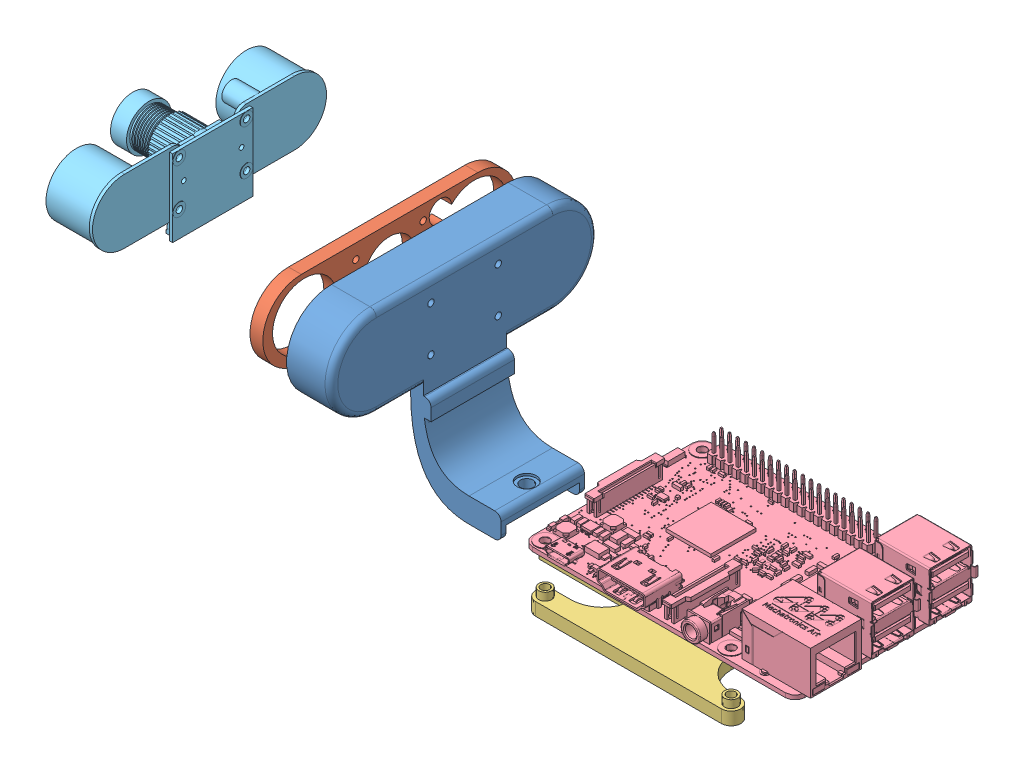
SolidWorks assembly Assem1, configuration Default. Lengths in mm.
Overall size (236.84 58 83.09).
5 component instances, 5 part files, 11 mates.
Components (placement in the parent):
- coverbase-1: coverbase [Default] at (37.3984 -15.5454 69.6534) x (0 0 1) z (-1 0 0) size (83.09 58 38.24)
- coverfront-1: coverfront [Default] at (13.9856 -17.5454 69.6493) x (0 0 1) z (-1 0 0) size (79.08 27.03 4)
- basecover-1: basecover [Default] at (103.6541 -46.1655 93.5452) size (76.61 6.4 55)
- Raspberry Pi 3-1: Raspberry Pi 3 [Default] at (131.8364 -28.3463 80.8971) x (1 0 0) z (0 1 0) size (89.64 57.31 18.59)
- Camera Module NVision Assem-1: Camera Module NVision Assem [Default] at (-21.6732 -17.5454 69.6534) x (0 0 1) z (-1 0 0) size (73 25 24.98)
Mates (geometry in assembly coordinates):
- Coincident1: coincident aligned: plane of coverbase-1 through (51.6361 -46.1655 65.4864) normal (0 -1 0); plane of basecover-1 through (103.6541 -46.1655 93.5452) normal (0 -1 0)
- Parallel1: parallel aligned: plane of coverbase-1 through (33.3984 -15.5454 65.4864) normal (0 0 -1); plane of basecover-1 through (103.6541 -42.1655 66.9864) normal (0 0 -1)
- Coincident4: coincident anti-aligned: plane of coverbase-1 through (52.6361 -46.1655 89.9864) normal (0 0 -1); plane of basecover-1 through (103.6541 -42.1655 89.9864) normal (0 0 1)
- Parallel2: parallel anti-aligned: plane of basecover-1 through (103.6541 -42.1655 93.5452) normal (0 1 0); plane of Raspberry Pi 3-1 through (168.3186 -28.6763 50.4864) normal (0 -1 0)
- Parallel3: parallel aligned: plane of coverbase-1 through (33.3984 -15.5454 65.4864) normal (0 0 -1); plane of Raspberry Pi 3-1 through (153.2454 -12.3553 52.7471) normal (0 0 -1)
- Concentric2: concentric anti-aligned: cylinder of basecover-1 through (86.8944 -42.1655 102.9864) axis (0 -1 0) radius 1.375; cylinder of Raspberry Pi 3-1 through (86.8944 -29.0963 102.9864) axis (0 1 0) radius 1.375
- Parallel4: parallel anti-aligned: plane of coverbase-1 through (33.3984 -15.5454 69.6534) normal (-1 0 0); plane of coverfront-1 through (13.9856 -2.1664 51.0813) normal (1 0 0)
- Coincident10: coincident anti-aligned: plane of coverbase-1 through (23.3984 9.8336 69.6534) normal (0 -1 0); plane of coverfront-1 through (9.9856 9.8336 51.0813) normal (0 1 0)
- Concentric3: concentric aligned: cylinder of coverbase-1 through (23.3984 -2.1664 51.0813) axis (1 0 0) radius 12; cylinder of coverfront-1 through (9.9856 -2.1664 51.0813) axis (1 0 0) radius 12
- Concentric4: concentric anti-aligned: cylinder of coverbase-1 through (33.3984 5.3056 89.127) axis (1 0 0) radius 1; cylinder of Camera Module NVision Assem-1 through (-40.1846 5.3056 89.127) axis (-1 0 0) radius 1
- Concentric5: concentric anti-aligned: cylinder of coverbase-1 through (33.3984 5.3056 68.127) axis (1 0 0) radius 1; cylinder of Camera Module NVision Assem-1 through (-41.2846 5.3056 68.127) axis (-1 0 0) radius 1
